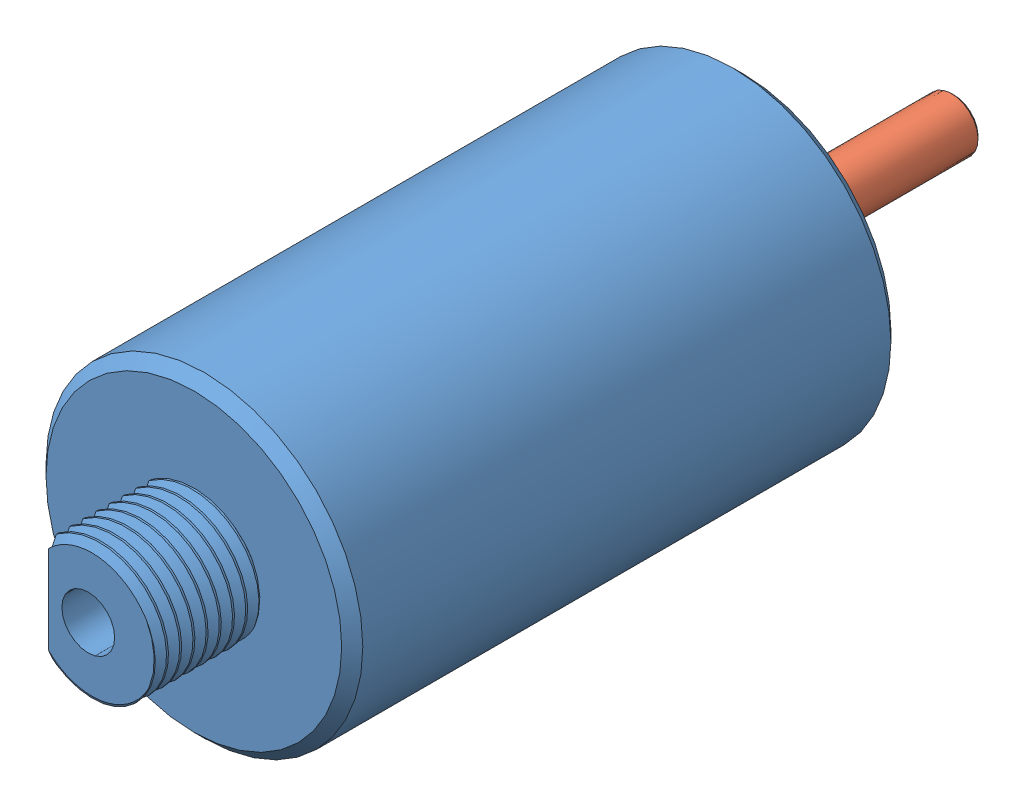
SolidWorks assembly Roll and nippel, configuration Default. Lengths in mm.
Overall size (6 6 16.48).
2 component instances, 2 part files, 2 mates.
Components (placement in the parent):
- Roll-1: Roll [Default] at (4.7741 9.2411 7.8106) size (6 6 12.59)
- Nippel-1: Nippel [Default] at (4.7741 9.2411 7.8106) x (-0.054091 0.998536 0) z (0 0 1) size (2.01 2.31 8.5)
Mates (geometry in assembly coordinates):
- Concentric1: concentric: circle of Roll-1; circle of Nippel-1
- Distance1: distance = 0 mm: plane of Nippel-1 through (4.7741 9.2411 7.8106) normal (0 0 -1); plane of Roll-1 through (4.7741 9.2411 7.8106) normal (0 0 -1)
